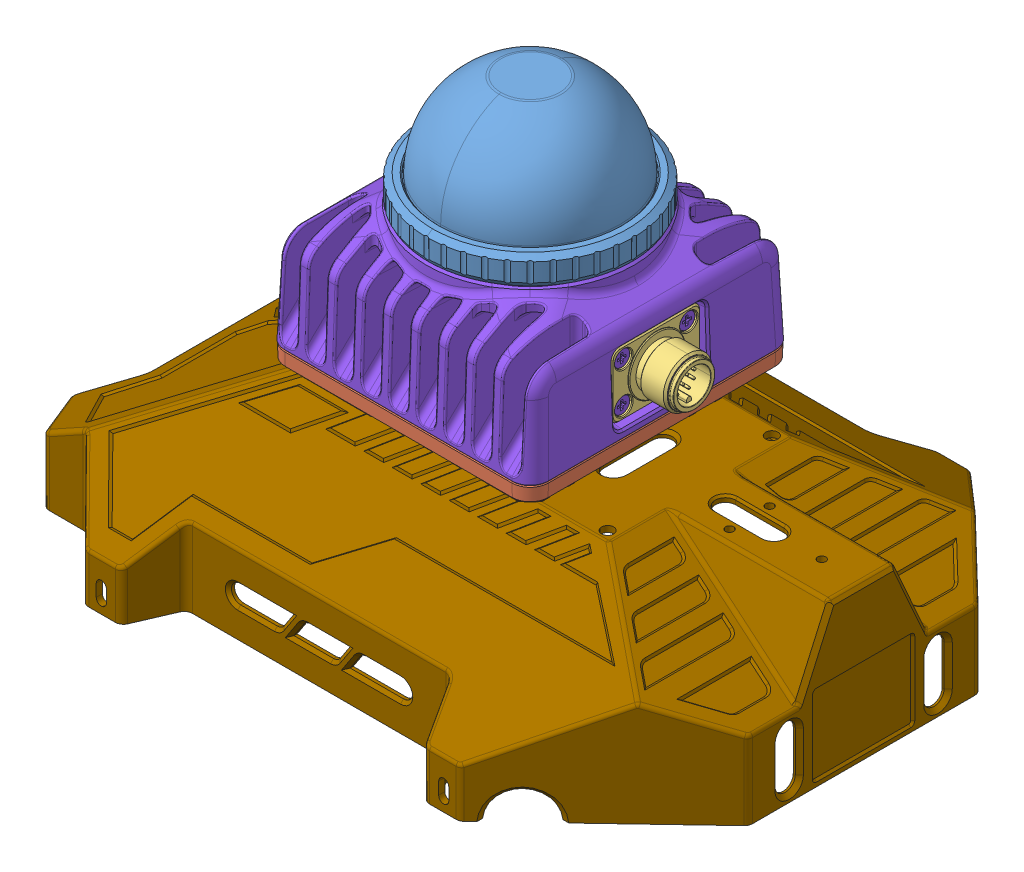
SolidWorks assembly 装配体2, configuration 默认. Lengths in mm.
Overall size (164.17 104.65 125.63).
12 component instances, 11 part files, 9 mates.
Components (placement in the parent):
- mid-360-asm.stp-1: mid-360-asm.stp [默认] at (-1.0339 -0.8315 72.7442) size (72.74 60.14 66.87)
  - MID-360_4_1.stp-1: MID-360_4_1.stp [默认] at origin size (51.01 27.17 51.01)
  - MID-360_4_2.stp-1: MID-360_4_2.stp [默认] at origin size (64.79 8.1 64.79)
  - MID-360_4_3.stp-1: MID-360_4_3.stp [默认] at origin size (13.8 16 22)
  - MID-360_4_4.stp-1: MID-360_4_4.stp [默认] at origin size (0.41 0.09 0.09)
  - MID-360_4_5.stp-1: MID-360_4_5.stp [默认] at origin size (0.41 0.09 0.09)
  - MID-360_4_6.stp-1: MID-360_4_6.stp [默认] at origin size (0.41 0.09 0.09)
  - MID-360_4_7.stp-1: MID-360_4_7.stp [默认] at origin size (0.41 0.09 0.09)
  - MID-360_4_ASM.stp-1: MID-360_4_ASM.stp [默认] at origin size (71.75 36.34 66.87)
- 顶壳.stp-1: 顶壳.stp [默认] at (1.4661 -71.2486 72.7442) x (0 0 -1) z (1 0 0) size (125.63 37.99 164.17)
- 零件12-1: 零件12 [默认] at (-1.0339 -28.7486 72.7442) x (0 0 -1) z (0 1 0) size (47.72 59.72 7)
- 零件11-1: 零件11 [默认] at (-1.0339 -30.7486 72.7442) x (0 0 -1) z (0 -1 0) size (50 50 3)
Mates (geometry in assembly coordinates):
- 重合2: coincident: plane of 顶壳.stp-1 through (41.4661 -33.7486 72.7442) normal (0 1 0); plane of 零件11-1 through (-1.0339 -33.7486 72.7442) normal (0 -1 0)
- 同心5: concentric: cylinder of 顶壳.stp-1 through (20.2161 -33.7486 93.9942) axis (0 -1 0) radius 1.25; cylinder of 零件11-1 through (20.2161 -33.7486 93.9942) axis (0 1 0) radius 1.25
- 重合3: coincident: plane of 顶壳.stp-1 through (41.4661 -33.7486 72.7442) normal (0 1 0); plane of 零件12-1 through (-1.0339 -33.7486 72.7442) normal (0 -1 0)
- 同心6: concentric anti-aligned: cylinder of 零件12-1 through (20.2161 -21.7486 93.9942) axis (0 -1 0) radius 1.5; cylinder of 零件11-1 through (20.2161 -33.7486 93.9942) axis (0 1 0) radius 1.25
- 重合4: coincident anti-aligned: plane of mid-360-asm.stp-1/MID-360_4_2.stp-1 through (-1.0339 -26.7486 72.7442) normal (0 -1 0); plane of 零件12-1 through (-1.0339 -26.7486 72.7442) normal (0 1 0)
- 同心8: concentric aligned: cylinder of mid-360-asm.stp-1/MID-360_4_2.stp-1 through (22.9661 -21.6526 90.7442) axis (0 -1 0) radius 1.25; cylinder of 零件12-1 through (22.9661 -26.7486 90.7442) axis (0 -1 0) radius 1.55
- 同心9: concentric aligned: cylinder of mid-360-asm.stp-1/MID-360_4_2.stp-1 through (-25.0339 -21.6526 54.7442) axis (0 -1 0) radius 1.25; cylinder of 零件12-1 through (-25.0339 -26.7486 54.7442) axis (0 -1 0) radius 1.55
- 同心10: concentric aligned: cylinder of 零件12-1 through (-26.0339 -33.7486 72.7442) axis (0 1 0) radius 14; cylinder of 零件11-1 through (-26.0339 -33.7486 72.7442) axis (0 1 0) radius 14
- 同心11: concentric anti-aligned: cylinder of 顶壳.stp-1 through (-22.2839 -33.7486 51.4942) axis (0 -1 0) radius 1.25; cylinder of 零件11-1 through (-22.2839 -33.7486 51.4942) axis (0 1 0) radius 1.25
